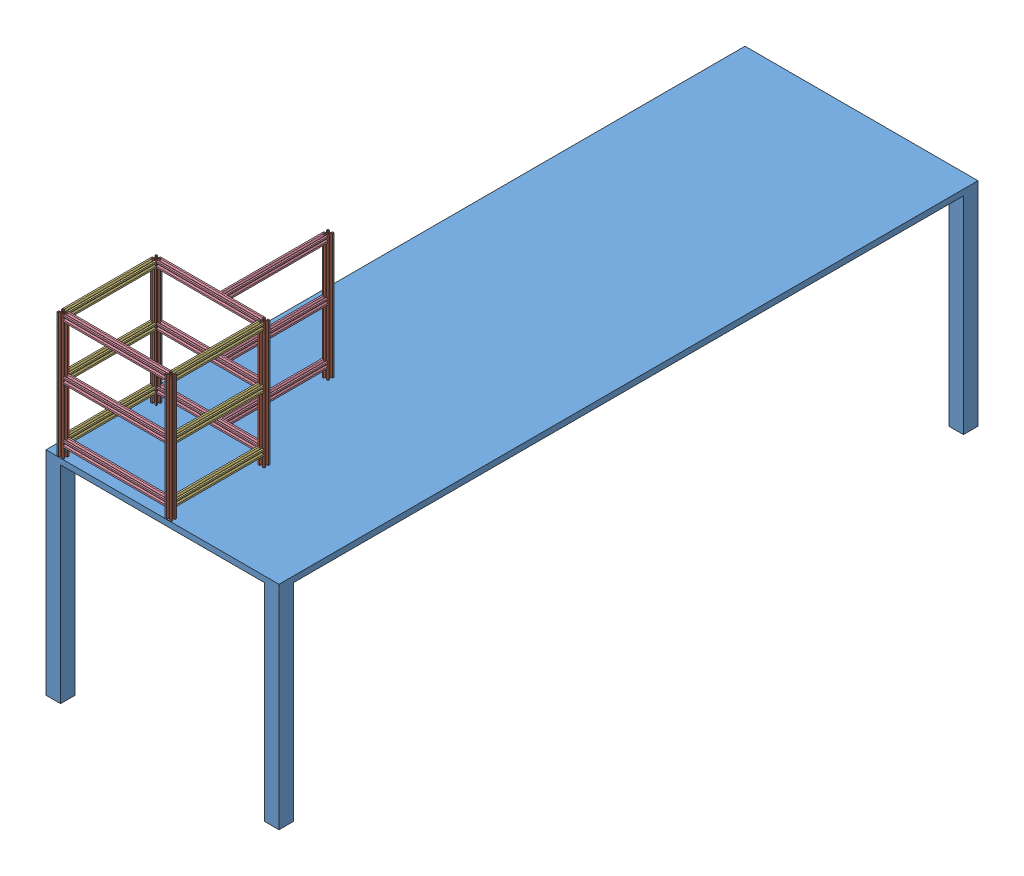
SolidWorks assembly desktotal, configuration 默认. Lengths in mm.
Overall size (800 1160 2400).
26 component instances, 5 part files, 14 mates.
Components (placement in the parent):
- desk-1: desk [默认] at (68.0483 280.8402 2400) size (800 730 2400)
- singal-1: singal [默认] at (-313.4062 507.2322 3485.5972) x (0 0 -1) z (1 0 0) size (340 430 390)
  - 2020lv_430-1: 2020lv_430 [默认] at (-104.4028 -206.392 400) size (20 430 20)
  - 2020lv_430-2: 2020lv_430 [默认] at (215.5972 -206.392 30) size (20 430 20)
  - 2020lv_430-3: 2020lv_430 [默认] at (-104.4028 -206.392 30) size (20 430 20)
  - 2020lv_430-4: 2020lv_430 [默认] at (215.5972 -206.392 400) size (20 430 20)
  - 2020lv_300-1: 2020lv_300 [默认] at (205.5972 -160.1212 400) x (0 1 0) z (0 0 1) size (20 300 20)
  - 2020lv_350-1: 2020lv_350 [默认] at (-104.4028 -160.1212 40) x (-1 0 0) z (0 1 0) size (20 350 20)
  - 2020lv_300-2: 2020lv_300 [默认] at (205.5972 -160.1212 30) x (0 1 0) z (0 0 1) size (20 300 20)
  - 2020lv_350-3: 2020lv_350 [默认] at (215.5972 -160.1212 40) x (-1 0 0) z (0 1 0) size (20 350 20)
  - 2020jiaocao-1: 2020jiaocao [默认] at (-104.5028 -167.1212 40) x (0 -1 0) z (-1 0 0) size (25 26 10)
  - 2020jiaocao-2: 2020jiaocao [默认] at (-104.5028 -167.1212 390) x (0 -1 0) z (1 0 0) size (25 26 10)
  - 2020jiaocao-3: 2020jiaocao [默认] at (-94.4028 -167.1212 29.9) x (0 -1 0) z (0 0 1) size (25 26 10)
  - 2020jiaocao-4: 2020jiaocao [默认] at (-94.4028 -167.1212 399.9) x (0 -1 0) z (0 0 1) size (25 26 10)
  - 2020lv_300-3: 2020lv_300 [默认] at (205.5972 28.6724 400) x (0 1 0) z (0 0 1) size (20 300 20)
  - 2020lv_300-4: 2020lv_300 [默认] at (205.5972 28.6724 30) x (0 1 0) z (0 0 1) size (20 300 20)
  - 2020lv_350-4: 2020lv_350 [默认] at (215.5972 28.6724 40) x (-1 0 0) z (0 1 0) size (20 350 20)
  - 2020lv_350-5: 2020lv_350 [默认] at (-104.4028 28.6724 40) x (-1 0 0) z (0 1 0) size (20 350 20)
  - 2020lv_350-6: 2020lv_350 [默认] at (215.5972 213.608 40) x (-1 0 0) z (0 1 0) size (20 350 20)
  - 2020lv_350-7: 2020lv_350 [默认] at (-104.4028 213.608 40) x (-1 0 0) z (0 1 0) size (20 350 20)
  - 2020lv_300-5: 2020lv_300 [默认] at (205.5972 213.608 30) x (0 1 0) z (0 0 1) size (20 300 20)
  - 2020lv_300-6: 2020lv_300 [默认] at (205.5972 213.608 400) x (0 1 0) z (0 0 1) size (20 300 20)
- 2020lv_350-1: 2020lv_350 [默认] at (-63.4062 347.111 2910) x (1 0 0) z (0 -1 0) size (20 350 20)
- 2020lv_350-3: 2020lv_350 [默认] at (-63.4062 535.9046 2910) x (1 0 0) z (0 -1 0) size (20 350 20)
- 2020lv_430-1: 2020lv_430 [默认] at (-63.4062 300.8402 2900) size (20 430 20)
- 2020lv_350-4: 2020lv_350 [默认] at (-63.4062 720.8402 2910) x (1 0 0) z (0 -1 0) size (20 350 20)
Mates (geometry in assembly coordinates):
- 重合1: coincident anti-aligned: plane of desk-1 through (68.0483 300.8402 2400) normal (0 1 0); plane of singal-1/2020lv_430-2 through (-283.4062 300.8402 3270) normal (0 -1 0)
- 重合2: coincident aligned: plane of desk-1 through (-331.9517 300.8402 3600) normal (0 0 1); plane of singal-1/2020lv_430-1 through (76.5938 730.8402 3600) normal (0 0 1)
- 重合3: coincident aligned: plane of singal-1/2020lv_350-3 through (76.5938 357.111 3260) normal (0 1 0); plane of 2020lv_350-1 through (-53.4062 357.111 3260) normal (0 1 0)
- 重合4: coincident anti-aligned: plane of singal-1/2020lv_350-3 through (76.5938 337.111 3260) normal (0 0 -1); plane of 2020lv_350-1 through (-63.4062 347.111 3260) normal (0 0 1)
- 距离1: distance = 200 mm anti-aligned: plane of 2020lv_350-1 through (-73.4062 357.111 3260) normal (-1 0 0); plane of singal-1/2020lv_430-2 through (-273.4062 730.8402 3280) normal (1 0 0)
- 重合7: coincident aligned: plane of singal-1/2020lv_350-4 through (76.5938 545.9046 3280) normal (0 1 0); plane of 2020lv_350-3 through (-73.4062 545.9046 3260) normal (0 1 0)
- 重合8: coincident aligned: plane of 2020lv_350-1 through (-53.4062 357.111 3260) normal (1 0 0); plane of 2020lv_350-3 through (-53.4062 545.9046 3260) normal (1 0 0)
- 重合9: coincident aligned: plane of 2020lv_350-1 through (-63.4062 347.111 2910) normal (0 0 -1); plane of 2020lv_350-3 through (-63.4062 535.9046 2910) normal (0 0 -1)
- 重合10: coincident aligned: plane of 2020lv_350-1 through (-53.4062 357.111 3260) normal (1 0 0); plane of 2020lv_430-1 through (-53.4062 730.8402 2890) normal (1 0 0)
- 重合11: coincident anti-aligned: plane of 2020lv_350-1 through (-63.4062 347.111 2910) normal (0 0 -1); plane of 2020lv_430-1 through (-73.4062 730.8402 2910) normal (0 0 1)
- 重合12: coincident aligned: plane of singal-1/2020lv_350-6 through (76.5938 730.8402 3260) normal (0 1 0); plane of 2020lv_430-1 through (-63.4062 730.8402 2900) normal (0 1 0)
- 重合13: coincident aligned: plane of 2020lv_350-3 through (-53.4062 545.9046 3260) normal (1 0 0); plane of 2020lv_350-4 through (-53.4062 730.8402 3260) normal (1 0 0)
- 重合14: coincident anti-aligned: plane of 2020lv_430-1 through (-73.4062 730.8402 2910) normal (0 0 1); plane of 2020lv_350-4 through (-63.4062 720.8402 2910) normal (0 0 -1)
- 重合15: coincident aligned: plane of 2020lv_430-1 through (-63.4062 730.8402 2900) normal (0 1 0); plane of 2020lv_350-4 through (-73.4062 730.8402 3260) normal (0 1 0)
